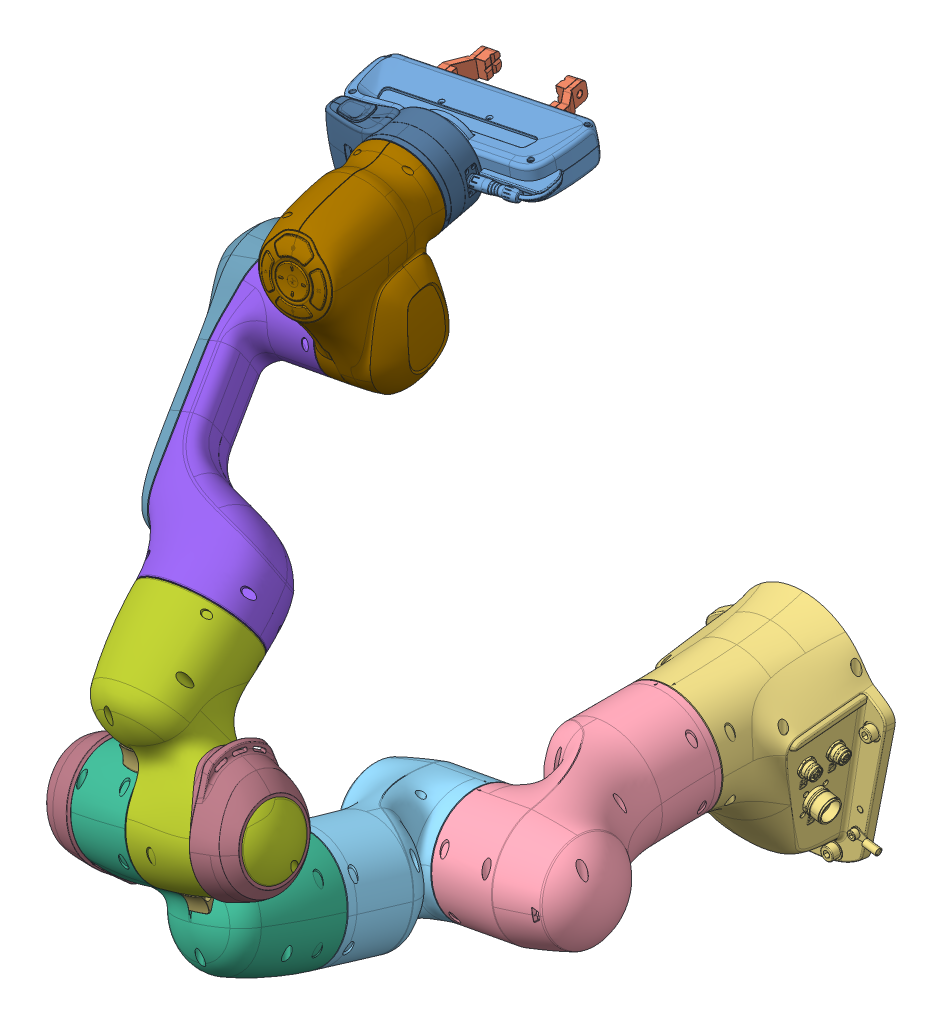
SolidWorks assembly FRANKA_including_FE_hand, configuration Predeterminado. Lengths in mm.
Overall size (707.07 799.73 813.31).
20 component instances, 14 part files, 0 mates.
Components (placement in the parent):
- FRANKA_including_FE_hand.STEP-1: FRANKA_including_FE_hand.STEP [Predeterminado] at origin size (707.07 799.73 813.31)
  - FRANKA_Hand_movable_Standard^FRANKA_including_FE_hand.STEP-1: FRANKA_Hand_movable_Standard^FRANKA_including_FE_hand.STEP [Predeterminado] at (-216.4758 521.0508 206.885) x (0.98687 0.106262 -0.121642) z (-0.130633 0.082187 -0.988018) size (209.36 63 139.49)
    - FRANKA_Hand_Standard^FRANKA_Hand_movable_Standard_FRANKA_including_FE_hand.STEP-1: FRANKA_Hand_Standard^FRANKA_Hand_movable_Standard_FRANKA_including_FE_hand.STEP [Predeterminado] at origin size (209.36 63 100.72)
    - FRANKA_Finger_Standard^FRANKA_Hand_movable_Standard_FRANKA_including_FE_hand.STEP-1: FRANKA_Finger_Standard^FRANKA_Hand_movable_Standard_FRANKA_including_FE_hand.STEP [Predeterminado] at (-31.2912 0 0) size (28.5 21 54)
    - FRANKA_Finger_Standard^FRANKA_Hand_movable_Standard_FRANKA_including_FE_hand.STEP-2: FRANKA_Finger_Standard^FRANKA_Hand_movable_Standard_FRANKA_including_FE_hand.STEP [Predeterminado] at (192.2912 0 0) x (-1 0 0) z (0 0 1) size (28.5 21 54)
  - BA_J1_adapted_Standard^FRANKA_including_FE_hand.STEP-1: BA_J1_adapted_Standard^FRANKA_including_FE_hand.STEP [Predeterminado] at origin size (190.41 246.49 162.25)
  - SH_J1J2_adapted_Standard^FRANKA_including_FE_hand.STEP-1: SH_J1J2_adapted_Standard^FRANKA_including_FE_hand.STEP [Predeterminado] at (0 0 333) x (-0.183194 0.983077 0) z (0.983077 0.183194 0) size (115.32 251.62 199.65)
  - SH_J2J3_adapted_Standard^FRANKA_including_FE_hand.STEP-1: SH_J2J3_adapted_Standard^FRANKA_including_FE_hand.STEP [Predeterminado] at (0 0 333) x (-0.176832 0.948936 -0.261251) z (-0.983077 -0.183194 0) size (115.32 254.62 199.65)
  - EL_J3J4_adapted_Standard^FRANKA_including_FE_hand.STEP-1: EL_J3J4_adapted_Standard^FRANKA_including_FE_hand.STEP [Predeterminado] at (-9.2393 49.5809 519.3456) x (0.968553 0.248156 -0.018005) z (-0.047859 0.25683 0.965271) size (168.02 294.04 179.56)
  - EL_J4J5_adapted_Standard^FRANKA_including_FE_hand.STEP-1: EL_J4J5_adapted_Standard^FRANKA_including_FE_hand.STEP [Predeterminado] at (-70.2021 290.4553 559.8167) x (-0.968553 -0.248156 0.018005) z (0.15193 -0.532571 0.832638) size (168.02 294.05 184.56)
  - LA_J5J6_adapted_Standard^FRANKA_including_FE_hand.STEP-1: LA_J5J6_adapted_Standard^FRANKA_including_FE_hand.STEP [Predeterminado] at (-70.3616 291.0145 558.9424) x (0.008677 -0.841666 -0.539929) z (-0.15193 0.532571 -0.832638) size (162.89 590.44 450.77)
  - WR_J6_adapted_Standard^FRANKA_including_FE_hand.STEP-1: WR_J6_adapted_Standard^FRANKA_including_FE_hand.STEP [Predeterminado] at (-116.7323 516.8327 350.6309) x (-0.078057 0.992612 0.09289) z (0.988353 0.089256 -0.123253) size (211.94 250.58 301.08)
  - WR_J7_adapted_Standard^FRANKA_including_FE_hand.STEP-1: WR_J7_adapted_Standard^FRANKA_including_FE_hand.STEP [Predeterminado] at (-116.7323 516.8327 350.6309) x (-0.630653 -0.775836 0.018846) z (-0.764991 0.625558 0.153182) size (125.55 54.81 125.55)
  - CLAMPING_PROTECTOR_ELBOW_adapted_Standard^FRANKA_including_FE_hand.STEP-1: CLAMPING_PROTECTOR_ELBOW_adapted_Standard^FRANKA_including_FE_hand.STEP [Predeterminado] at (-70.2021 290.4553 559.8167) x (-0.968553 -0.248156 0.018005) z (0.15193 -0.532571 0.832638) size (22.1 30.05 50.92)
  - CLAMPING_PROTECTOR_ELBOW_adapted_Standard^FRANKA_including_FE_hand.STEP-2: CLAMPING_PROTECTOR_ELBOW_adapted_Standard^FRANKA_including_FE_hand.STEP [Predeterminado] at (-9.2393 49.5809 519.3456) x (0.968553 0.248156 -0.018005) z (-0.047859 0.25683 0.965271) size (22.1 30.05 50.92)
  - CLAMPING_PROTECTOR_ELBOW_SMALL_adapted_Standard^FRANKA_including_FE_hand.STEP-1: CLAMPING_PROTECTOR_ELBOW_SMALL_adapted_Standard^FRANKA_including_FE_hand.STEP [Predeterminado] at (-70.2021 290.4553 559.8167) x (-0.968553 -0.248156 0.018005) z (0.15193 -0.532571 0.832638) size (22.3 27.95 23.1)
  - CLAMPING_PROTECTOR_ELBOW_SMALL_adapted_Standard^FRANKA_including_FE_hand.STEP-2: CLAMPING_PROTECTOR_ELBOW_SMALL_adapted_Standard^FRANKA_including_FE_hand.STEP [Predeterminado] at (-9.2393 49.5809 519.3456) x (0.968553 0.248156 -0.018005) z (-0.047859 0.25683 0.965271) size (22.3 27.95 23.1)
  - ELBOW_PROTECTOR_adapted_Standard^FRANKA_including_FE_hand.STEP-1: ELBOW_PROTECTOR_adapted_Standard^FRANKA_including_FE_hand.STEP [Predeterminado] at (-51.5945 203.1564 476.3319) x (0.968553 0.248156 -0.018005) z (-0.047859 0.25683 0.965271) size (343.15 146.88 137.09)
  - ELBOW_PROTECTOR_adapted_Standard^FRANKA_including_FE_hand.STEP-2: ELBOW_PROTECTOR_adapted_Standard^FRANKA_including_FE_hand.STEP [Predeterminado] at (-35.6279 157.4963 468.4049) x (-0.968553 -0.248156 0.018005) z (0.15193 -0.532571 0.832638) size (343.15 146.88 137.09)
  - LOWER_ARM_PROTECTOR_adapted_Standard^FRANKA_including_FE_hand.STEP-1: LOWER_ARM_PROTECTOR_adapted_Standard^FRANKA_including_FE_hand.STEP [Predeterminado] at (-70.3616 291.0145 558.9424) x (0.008677 -0.841666 -0.539929) z (-0.15193 0.532571 -0.832638) size (101.02 98.32 264.83)
